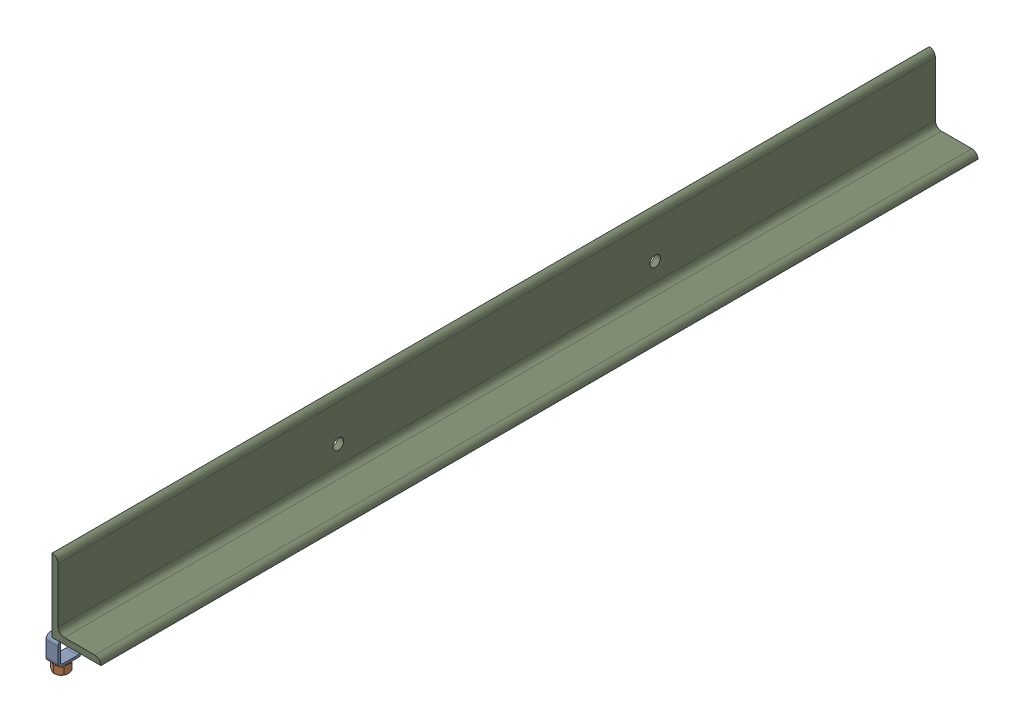
SolidWorks assembly 01-003-00-0-1, configuration Default. Lengths in mm.
Overall size (115.89 220.09 1828.8).
13 component instances, 3 part files, 0 mates.
Components (placement in the parent):
- 01-005-00-0-10-1: 01-005-00-0-10 [Default] at (-6.35 0 863.6) x (0 -1 0) z (-1 0 0) size (67.69 50.8 28.57)
  - tube square_ai(PreviewCfg)-1: tube square_ai(PreviewCfg) [Default] at origin size (50.8 50.8 25.4)
  - hex nut_ai(HNUT 0.7500-10-D-C)-1: hex nut_ai(HNUT 0.7500-10-D-C) [Default] at (67.691 31.75 0) x (0 0 -1) z (1 0 0) size (28.57 33 16.89)
- 01-005-00-0-11-1: 01-005-00-0-11 [Default] at (-6.35 0 -914.4) x (0 -1 0) z (-1 0 0) size (67.69 50.8 28.57)
  - tube square_ai(PreviewCfg)-1: tube square_ai(PreviewCfg) [Default] at origin size (50.8 50.8 25.4)
  - hex nut_ai(HNUT 0.7500-10-D-C)-1: hex nut_ai(HNUT 0.7500-10-D-C) [Default] at (67.691 31.75 0) x (0 0 -1) z (1 0 0) size (28.57 33 16.89)
- 01-005-00-0-12-1: 01-005-00-0-12 [Default] at (-6.35 0 -609.6) x (0 -1 0) z (-1 0 0) size (67.69 50.8 28.57)
  - tube square_ai(PreviewCfg)-1: tube square_ai(PreviewCfg) [Default] at origin size (50.8 50.8 25.4)
  - hex nut_ai(HNUT 0.7500-10-D-C)-1: hex nut_ai(HNUT 0.7500-10-D-C) [Default] at (67.691 31.75 0) x (0 0 -1) z (1 0 0) size (28.57 33 16.89)
- 01-005-00-0-13-1: 01-005-00-0-13 [Default] at (-6.35 0 558.8) x (0 -1 0) z (-1 0 0) size (67.69 50.8 28.57)
  - tube square_ai(PreviewCfg)-1: tube square_ai(PreviewCfg) [Default] at origin size (50.8 50.8 25.4)
  - hex nut_ai(HNUT 0.7500-10-D-C)-1: hex nut_ai(HNUT 0.7500-10-D-C) [Default] at (67.691 31.75 0) x (0 0 -1) z (1 0 0) size (28.57 33 16.89)
- 01-004-00-0-1: 01-004-00-0 [Default] at (-6.35 0 0) size (101.6 152.4 1828.8)
